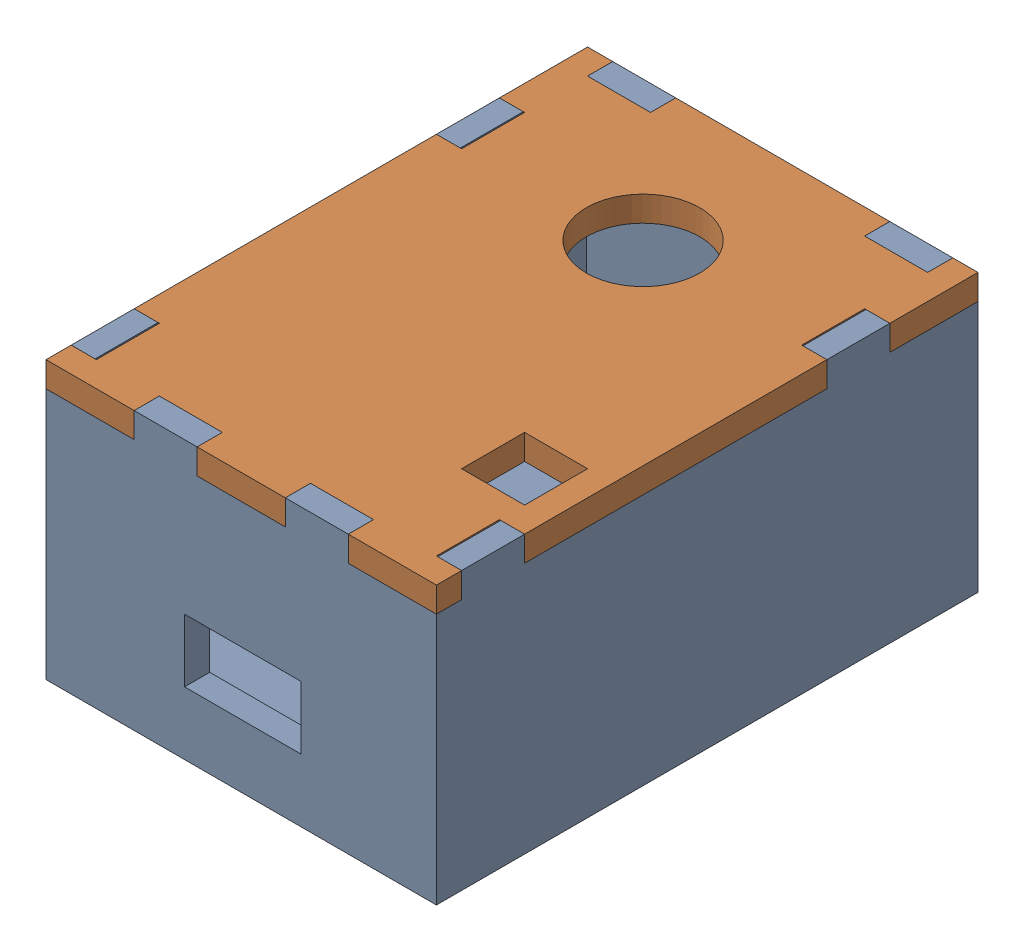
SolidWorks assembly Assem1, configuration Default. Lengths in mm.
Overall size (31 22 43).
2 component instances, 2 part files, 3 mates.
Components (placement in the parent):
- buttom part-1: buttom part [Default] at (10.6595 10.4731 24.4123) size (31 22 43)
- top part-1: top part [Default] at (10.6595 30.4731 24.4123) size (31 2 43)
Mates (geometry in assembly coordinates):
- Coincident1: coincident: line of buttom part-1 through (-4.8405 30.4731 45.9123) axis (1 0 0); line of top part-1 through (-4.8405 30.4731 45.9123) axis (1 0 0)
- Coincident2: coincident: plane of buttom part-1 through (2.1595 10.4731 43.9123) normal (-1 0 0); plane of top part-1 through (2.1595 33.8905 24.6856) normal (1 0 0)
- Coincident4: coincident anti-aligned: line of buttom part-1 through (-4.8405 30.4731 9.9123) axis (0 0 -1); line of top part-1 through (-4.8405 30.4731 2.9123) axis (0 0 1)
